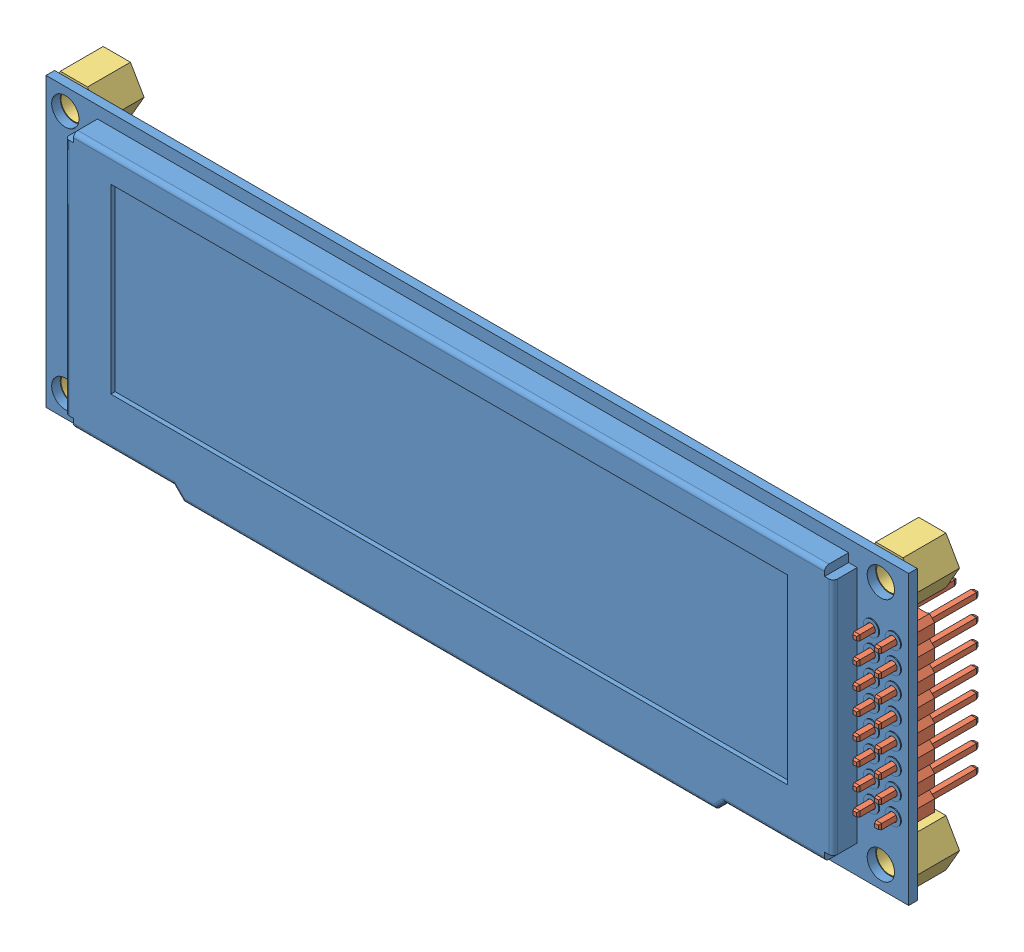
SolidWorks assembly OLED_ASM, configuration По умолчанию. Lengths in mm.
Overall size (102.94 36.75 12.4).
6 component instances, 3 part files, 15 mates.
Components (placement in the parent):
- OLED_3_12_Module-1: OLED_3_12_Module [По умолчанию] at origin size (100.5 33.5 3.8)
- PLD-16.step-1: PLD-16.step [По умолчанию] at (48.5 9.14 0) x (0 -1 0) z (0 0 -1) size (20.32 5.08 11.6)
- SpacerM3_5-1: SpacerM3_5 [По умолчанию] at (47 14.25 -5) x (0.866025 0.5 0) z (0 0 1) size (5.5 6.35 5)
- SpacerM3_5-2: SpacerM3_5 [По умолчанию] at (-48 14.25 -5) x (0.866025 -0.5 0) z (0 0 1) size (5.5 6.35 5)
- SpacerM3_5-3: SpacerM3_5 [По умолчанию] at (47 -14.25 -5) x (0.866025 -0.5 0) z (0 0 1) size (5.5 6.35 5)
- SpacerM3_5-4: SpacerM3_5 [По умолчанию] at (-48 -14.25 -5) x (0.866025 -0.5 0) z (0 0 1) size (5.5 6.35 5)
Mates (geometry in assembly coordinates):
- Совпадение3: coincident anti-aligned: plane of OLED_3_12_Module-1 through (0 0 0) normal (0 0 -1); plane of PLD-16.step-1 through (48.5 9.14 0) normal (0 0 1)
- Параллельность2: parallel aligned: plane of OLED_3_12_Module-1 through (50.25 16.75 1) normal (1 0 0); plane of PLD-16.step-1 through (49.77 2.19 0) normal (1 0 0)
- Концентричный1: concentric: cylinder of OLED_3_12_Module-1 through (45.96 -8.64 0) axis (0 0 1) radius 0.5; point of PLD-16.step-1
- Совпадение8: coincident anti-aligned: plane of OLED_3_12_Module-1 through (0 0 0) normal (0 0 -1); plane of SpacerM3_5-1 through (47 14.25 0) normal (0 0 1)
- Концентричный3: concentric aligned: cylinder of OLED_3_12_Module-1 through (47 14.25 1) axis (0 0 -1) radius 1.6; cylinder of SpacerM3_5-1 through (47 14.25 0) axis (0 0 -1) radius 1.5
- Параллельность4: parallel aligned: plane of OLED_3_12_Module-1 through (-50.25 16.75 1) normal (0 1 0); plane of SpacerM3_5-1 through (48.5877 17 0) normal (0 1 0)
- Совпадение10: coincident anti-aligned: plane of OLED_3_12_Module-1 through (0 0 0) normal (0 0 -1); plane of SpacerM3_5-2 through (-48 14.25 0) normal (0 0 1)
- Концентричный4: concentric aligned: cylinder of OLED_3_12_Module-1 through (-48 14.25 1) axis (0 0 -1) radius 1.6; cylinder of SpacerM3_5-2 through (-48 14.25 0) axis (0 0 -1) radius 1.5
- Параллельность5: parallel aligned: plane of OLED_3_12_Module-1 through (-50.25 16.75 1) normal (0 1 0); plane of SpacerM3_5-2 through (-46.4123 17 0) normal (0 1 0)
- Совпадение12: coincident anti-aligned: plane of OLED_3_12_Module-1 through (0 0 0) normal (0 0 -1); plane of SpacerM3_5-3 through (47 -14.25 0) normal (0 0 1)
- Концентричный5: concentric aligned: cylinder of OLED_3_12_Module-1 through (47 -14.25 1) axis (0 0 -1) radius 1.6; cylinder of SpacerM3_5-3 through (47 -14.25 0) axis (0 0 -1) radius 1.5
- Параллельность6: parallel aligned: plane of OLED_3_12_Module-1 through (-50.25 -16.75 1) normal (0 -1 0); plane of SpacerM3_5-3 through (45.4123 -17 0) normal (0 -1 0)
- Совпадение14: coincident anti-aligned: plane of OLED_3_12_Module-1 through (0 0 0) normal (0 0 -1); plane of SpacerM3_5-4 through (-48 -14.25 0) normal (0 0 1)
- Концентричный6: concentric aligned: cylinder of OLED_3_12_Module-1 through (-48 -14.25 1) axis (0 0 -1) radius 1.6; cylinder of SpacerM3_5-4 through (-48 -14.25 0) axis (0 0 -1) radius 1.5
- Параллельность7: parallel aligned: plane of OLED_3_12_Module-1 through (-50.25 -16.75 1) normal (0 -1 0); plane of SpacerM3_5-4 through (-49.5877 -17 0) normal (0 -1 0)
